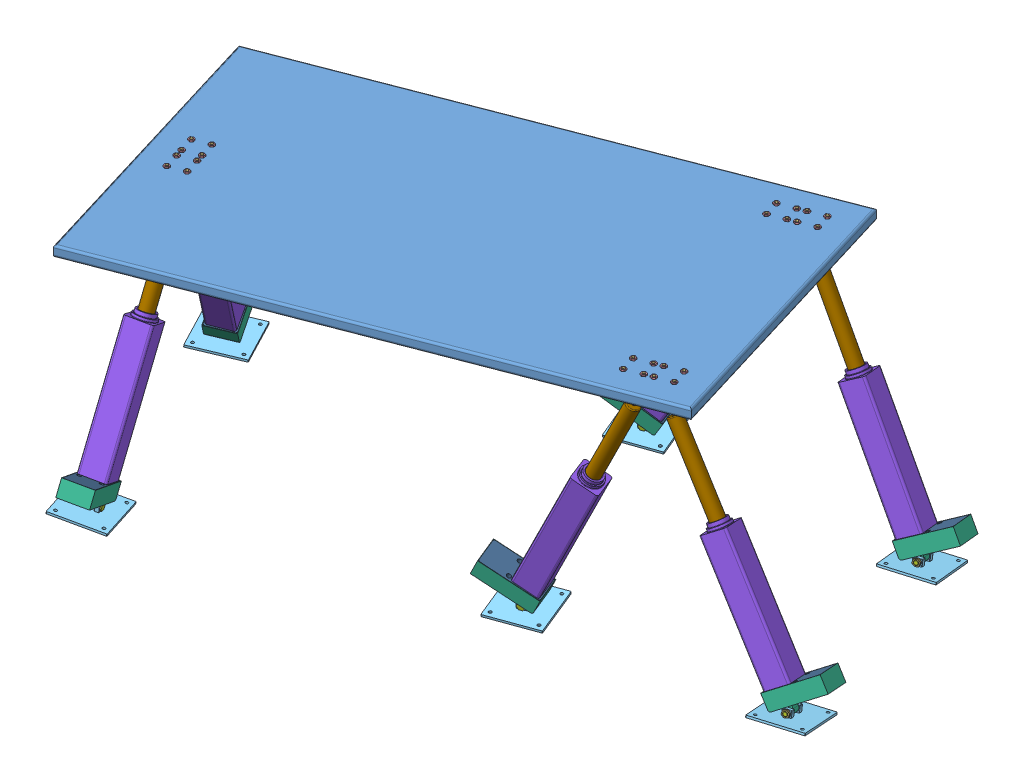
SolidWorks assembly assemblageComplet, configuration Défaut. Lengths in mm.
Overall size (3628.91 1350.38 2383.84).
122 component instances, 12 part files, 6 mates.
Components (placement in the parent):
- assemblagePlaque-1: assemblagePlaque [Défaut] at (1899.0462 -733.3274 2922.0616) x (-0.94396 -0.025016 0.32911) z (-0.327279 -0.058201 -0.943134) size (2500 133.05 1500)
  - plaque-1: plaque [Défaut] at (42.7083 65.3445 2500) size (2500 50 1500)
  - fixationPlaque-1: fixationPlaque [Défaut] at (1110.4083 29.9622 2320) x (-1 0 0) z (0 0 1) size (120 74.05 120)
    - attachePlaque-1: attachePlaque [Défaut] at (-12.3 -35.3823 120) size (120 74.05 120)
  - fixationPlaque-2: fixationPlaque [Défaut] at (1135.0083 29.9622 2680) x (1 0 0) z (0 0 -1) size (120 74.05 120)
    - attachePlaque-1: attachePlaque [Défaut] at (-12.3 -35.3823 120) size (120 74.05 120)
  - fixationPlaque-5: fixationPlaque [Défaut] at (-917.2917 29.9622 3067.7) x (0 0 -1) z (-1 0 0) size (120 74.05 120)
    - attachePlaque-1: attachePlaque [Défaut] at (-12.3 -35.3823 120) size (120 74.05 120)
  - fixationPlaque-6: fixationPlaque [Défaut] at (-797.2917 29.9622 3067.7) x (0 0 -1) z (-1 0 0) size (120 74.05 120)
    - attachePlaque-1: attachePlaque [Défaut] at (-12.3 -35.3823 120) size (120 74.05 120)
  - fixationPlaque-7: fixationPlaque [Défaut] at (-917.2917 29.9622 1907.7) x (0 0 -1) z (-1 0 0) size (120 74.05 120)
    - attachePlaque-1: attachePlaque [Défaut] at (-12.3 -35.3823 120) size (120 74.05 120)
  - fixationPlaque-8: fixationPlaque [Défaut] at (-797.2917 29.9622 1907.7) x (0 0 -1) z (-1 0 0) size (120 74.05 120)
    - attachePlaque-1: attachePlaque [Défaut] at (-12.3 -35.3823 120) size (120 74.05 120)
  - visPlaque-1: visPlaque [Défaut] at (-1077.2917 52.3445 3120) size (24.69 72 26.25)
  - ecrou-1: ecrou [Défaut] at (-1077.2917 115.3445 3120) size (24.81 7 26.32)
  - visPlaque-2: visPlaque [Défaut] at (-1077.2917 52.3445 3040) size (24.69 72 26.25)
  - visPlaque-3: visPlaque [Défaut] at (-997.2917 52.3445 3120) size (24.69 72 26.25)
  - visPlaque-4: visPlaque [Défaut] at (-957.2917 52.3445 3120) size (24.69 72 26.25)
  - visPlaque-5: visPlaque [Défaut] at (-997.2917 52.3445 3040) size (24.69 72 26.25)
  - visPlaque-7: visPlaque [Défaut] at (-957.2917 52.3445 3040) size (24.69 72 26.25)
  - visPlaque-9: visPlaque [Défaut] at (-877.2917 52.3445 3120) size (24.69 72 26.25)
  - visPlaque-10: visPlaque [Défaut] at (-877.2917 52.3445 3040) size (24.69 72 26.25)
  - visPlaque-11: visPlaque [Défaut] at (-877.2917 52.3445 1880) size (24.69 72 26.25)
  - visPlaque-12: visPlaque [Défaut] at (-957.2917 52.3445 1880) size (24.69 72 26.25)
  - visPlaque-13: visPlaque [Défaut] at (-877.2917 52.3445 1960) size (24.69 72 26.25)
  - visPlaque-14: visPlaque [Défaut] at (-957.2917 52.3445 1960) size (24.69 72 26.25)
  - visPlaque-15: visPlaque [Défaut] at (-997.2917 52.3445 1880) size (24.69 72 26.25)
  - visPlaque-16: visPlaque [Défaut] at (-1077.2917 52.3445 1960) size (24.69 72 26.25)
  - visPlaque-17: visPlaque [Défaut] at (-1077.2917 52.3445 1880) size (24.69 72 26.25)
  - visPlaque-18: visPlaque [Défaut] at (-997.2917 52.3445 1960) size (24.69 72 26.25)
  - visPlaque-19: visPlaque [Défaut] at (1162.7083 52.3445 2600) size (24.69 72 26.25)
  - visPlaque-20: visPlaque [Défaut] at (1082.7083 52.3445 2600) size (24.69 72 26.25)
  - visPlaque-21: visPlaque [Défaut] at (1082.7083 52.3445 2520) size (24.69 72 26.25)
  - visPlaque-22: visPlaque [Défaut] at (1162.7083 52.3445 2520) size (24.69 72 26.25)
  - visPlaque-23: visPlaque [Défaut] at (1162.7083 52.3445 2480) size (24.69 72 26.25)
  - visPlaque-25: visPlaque [Défaut] at (1162.7083 52.3445 2400) size (24.69 72 26.25)
  - visPlaque-26: visPlaque [Défaut] at (1082.7083 52.3445 2480) size (24.69 72 26.25)
  - visPlaque-27: visPlaque [Défaut] at (1082.7083 52.3445 2400) size (24.69 72 26.25)
  - ecrou-2: ecrou [Défaut] at (1162.7083 115.3445 2600) size (24.81 7 26.32)
  - ecrou-4: ecrou [Défaut] at (1082.7083 115.3445 2600) size (24.81 7 26.32)
  - ecrou-5: ecrou [Défaut] at (1082.7083 115.3445 2520) size (24.81 7 26.32)
  - ecrou-6: ecrou [Défaut] at (-997.2917 115.3445 3120) size (24.81 7 26.32)
  - ecrou-7: ecrou [Défaut] at (-1077.2917 115.3445 3040) size (24.81 7 26.32)
  - ecrou-8: ecrou [Défaut] at (-997.2917 115.3445 3040) size (24.81 7 26.32)
  - ecrou-9: ecrou [Défaut] at (-957.2917 115.3445 3040) size (24.81 7 26.32)
  - ecrou-11: ecrou [Défaut] at (-877.2917 115.3445 3040) size (24.81 7 26.32)
  - ecrou-12: ecrou [Défaut] at (-957.2917 115.3445 3120) size (24.81 7 26.32)
  - ecrou-13: ecrou [Défaut] at (-877.2917 115.3445 3120) size (24.81 7 26.32)
  - ecrou-14: ecrou [Défaut] at (-1077.2917 115.3445 1880) size (24.81 7 26.32)
  - ecrou-15: ecrou [Défaut] at (-997.2917 115.3445 1880) size (24.81 7 26.32)
  - ecrou-16: ecrou [Défaut] at (-957.2917 115.3445 1880) size (24.81 7 26.32)
  - ecrou-17: ecrou [Défaut] at (-1077.2917 115.3445 1960) size (24.81 7 26.32)
  - ecrou-18: ecrou [Défaut] at (-997.2917 115.3445 1960) size (24.81 7 26.32)
  - ecrou-19: ecrou [Défaut] at (-957.2917 115.3445 1960) size (24.81 7 26.32)
  - ecrou-20: ecrou [Défaut] at (-877.2917 115.3445 1960) size (24.81 7 26.32)
  - ecrou-21: ecrou [Défaut] at (-877.2917 115.3445 1880) size (24.81 7 26.32)
  - ecrou-22: ecrou [Défaut] at (1162.7083 115.3445 2520) size (24.81 7 26.32)
  - ecrou-23: ecrou [Défaut] at (1162.7083 115.3445 2480) size (24.81 7 26.32)
  - ecrou-24: ecrou [Défaut] at (1082.7083 115.3445 2480) size (24.81 7 26.32)
  - ecrou-25: ecrou [Défaut] at (1162.7083 115.3445 2400) size (24.81 7 26.32)
  - ecrou-26: ecrou [Défaut] at (1082.7083 115.3445 2400) size (24.81 7 26.32)
- AssemblementSocleVerin-1: AssemblementSocleVerin [Défaut] at (1913.4027 -2106.2601 67.4221) x (-0.342414 -0.059167 -0.937684) z (0.939482 -0.009636 -0.342463) size (387.8 1201.25 824.63) (flexible)
  - BaseFixationSol-1: BaseFixationSol [Défaut] at (119.3252 189.0503 636.1467) x (0.987313 -0.147005 0.060014) z (-0.059878 0.005348 0.998191) size (240 40 240)
  - BoitierVerin-1: BoitierVerin [Défaut] at (128.1715 273.9331 694.3702) x (-0.018422 -0.48146 -0.876275) z (0.987313 -0.147005 0.060014) size (263 115 133)
  - VisBoititerVerin-1: VisBoititerVerin [Défaut] at (167.4309 207.1631 638.9353) x (0.14706 0.989121 0.003522) z (-0.059878 0.005348 0.998191) size (30.46 97 34.64)
  - assemblageVerin-1: assemblageVerin [Défaut] at (232.7025 260.8151 321.2319) x (0.987484 -0.1387 0.07508) z (0.001434 0.483918 0.875112) size (134.45 1180.45 262.2)
    - BaseVerin-1: BaseVerin [Défaut] at (-78.391 -108.5334 268) size (120 679 120)
    - Verin-1: Verin [Défaut] at (-78.391 292.5867 268) x (-0.924202 0 0.381903) z (-0.381903 0 -0.924202) size (70 662 70)
    - supportMoteur-1: supportMoteur [Défaut] at (-77.2727 -178.5334 332.9904) x (0.017204 0 0.999852) z (-0.999852 0 0.017204) size (260 70 130)
    - attacheVerin-1: attacheVerin [Défaut] at (-78.391 924.5867 268) x (0.999999 0 -0.001089) z (0.001089 0 0.999999) size (40 77.33 40)
  - EcrouAxeSocle-1: EcrouAxeSocle [Défaut] at (83.5092 219.6585 633.8342) x (-0.155337 -0.972556 0.173218) z (0.032903 -0.180343 -0.983053) size (32.03 10 34.64)
- AssemblementSocleVerin-3: AssemblementSocleVerin [Défaut] at (2142.0561 -2104.9187 -0.2086) x (0.342446 0.057092 0.937801) z (-0.939335 0.000085 0.343001) size (381.88 1198.06 838.62) (flexible)
  - BaseFixationSol-1: BaseFixationSol [Défaut] at (-510.5909 194.7617 841.3259) x (0.986382 -0.164066 0.011569) z (-0.0114 0.001968 0.999933) size (240 40 240)
  - BoitierVerin-1: BoitierVerin [Défaut] at (-497.3086 280.161 898.3474) x (-0.071559 -0.491425 -0.867975) z (0.986382 -0.164066 0.011569) size (263 115 133)
  - VisBoititerVerin-1: VisBoititerVerin [Défaut] at (-462.1018 212.0399 841.8447) x (0.164078 0.986447 -0.000071) z (-0.0114 0.001968 0.999933) size (30.46 97 34.64)
  - assemblageVerin-1: assemblageVerin [Défaut] at (-412.2279 260.728 520.5715) x (0.987467 -0.155587 0.026499) z (0.054579 0.494174 0.867648) size (134.45 1180.45 262.2)
    - BaseVerin-1: BaseVerin [Défaut] at (-78.391 -108.5334 268) size (120 679 120)
    - Verin-1: Verin [Défaut] at (-78.391 292.5867 268) x (-0.924202 0 0.381903) z (-0.381903 0 -0.924202) size (70 662 70)
    - supportMoteur-1: supportMoteur [Défaut] at (-77.2727 -178.5334 332.9904) x (0.017204 0 0.999852) z (-0.999852 0 0.017204) size (260 70 130)
    - attacheVerin-1: attacheVerin [Défaut] at (-78.391 924.5867 268) x (0.999999 0 -0.001089) z (0.001089 0 0.999999) size (40 77.33 40)
  - EcrouAxeSocle-1: EcrouAxeSocle [Défaut] at (-545.9442 225.9855 840.8614) x (-0.163505 -0.970523 0.177062) z (-0.017822 -0.176543 -0.984132) size (32.03 10 34.64)
- AssemblementSocleVerin-4: AssemblementSocleVerin [Défaut] at (2303.8055 -2040.4411 1157.8281) x (-0.342402 -0.05932 -0.937679) z (0.939336 -0.000129 -0.342999) size (410.45 1184.18 870.06) (flexible)
  - BaseFixationSol-1: BaseFixationSol [Défaut] at (99.8117 226.2059 683.6223) x (0.984344 -0.162122 0.069157) z (-0.068951 0.006902 0.997596) size (240 40 240)
  - BoitierVerin-1: BoitierVerin [Défaut] at (110.0864 313.6973 738.8652) x (-0.026359 -0.523357 -0.851706) z (0.984344 -0.162122 0.069157) size (263 115 133)
  - VisBoititerVerin-1: VisBoititerVerin [Défaut] at (148.1624 243.579 686.844) x (0.162209 0.986747 0.004385) z (-0.068951 0.006902 0.997596) size (30.46 97 34.64)
  - assemblageVerin-1: assemblageVerin [Défaut] at (214.7817 280.3976 367.0305) x (0.984652 -0.153094 0.083799) z (0.009421 0.526069 0.85039) size (134.45 1180.45 262.2)
    - BaseVerin-1: BaseVerin [Défaut] at (-78.391 -108.5334 268) size (120 679 120)
    - Verin-1: Verin [Défaut] at (-78.391 292.5867 268) x (-0.924202 0 0.381903) z (-0.381903 0 -0.924202) size (70 662 70)
    - supportMoteur-1: supportMoteur [Défaut] at (-77.2727 -178.5334 332.9904) x (0.017204 0 0.999852) z (-0.999852 0 0.017204) size (260 70 130)
    - attacheVerin-1: attacheVerin [Défaut] at (-78.391 924.5867 268) x (0.999999 0 -0.001089) z (0.001089 0 0.999999) size (40 77.33 40)
  - EcrouAxeSocle-1: EcrouAxeSocle [Défaut] at (64.4932 257.3594 680.9656) x (-0.171853 -0.969944 0.172263) z (0.039151 -0.181451 -0.98262) size (32.03 10 34.64)
- AssemblementSocleVerin-5: AssemblementSocleVerin [Défaut] at (2523.5529 -2037.1167 1093.1655) x (0.342447 0.057118 0.937799) z (-0.939301 -0.001561 0.343091) size (344.77 1216.62 750.58) (flexible)
  - BaseFixationSol-1: BaseFixationSol [Défaut] at (-476.6519 139.447 741.7117) x (0.991223 -0.132151 0.003531) z (-0.003463 0.00074 0.999994) size (240 40 240)
  - BoitierVerin-1: BoitierVerin [Défaut] at (-466.4056 219.8573 804.0122) x (-0.051881 -0.413426 -0.909058) z (0.991223 -0.132151 0.003531) size (263 115 133)
  - VisBoititerVerin-1: VisBoititerVerin [Défaut] at (-428.743 158.2809 741.8636) x (0.132153 0.991229 -0.000276) z (-0.003463 0.00074 0.999994) size (30.46 97 34.64)
  - assemblageVerin-1: assemblageVerin [Défaut] at (-379.2667 237.274 426.6072) x (0.991969 -0.125019 0.019169) z (0.03482 0.415639 0.908863) size (134.45 1180.45 262.2)
    - BaseVerin-1: BaseVerin [Défaut] at (-78.391 -108.5334 268) size (120 679 120)
    - Verin-1: Verin [Défaut] at (-78.391 292.5867 268) x (-0.924202 0 0.381903) z (-0.381903 0 -0.924202) size (70 662 70)
    - supportMoteur-1: supportMoteur [Défaut] at (-77.2727 -178.5334 332.9904) x (0.017204 0 0.999852) z (-0.999852 0 0.017204) size (260 70 130)
    - attacheVerin-1: attacheVerin [Défaut] at (-78.391 924.5867 268) x (0.999999 0 -0.001089) z (0.001089 0 0.999999) size (40 77.33 40)
  - EcrouAxeSocle-1: EcrouAxeSocle [Défaut] at (-512.997 169.5138 741.5635) x (-0.130679 -0.975447 0.177275) z (-0.019983 -0.17618 -0.984155) size (32.03 10 34.64)
- AssemblementSocleVerin-6: AssemblementSocleVerin [Défaut] at (163.7194 -2034.6282 1098.1546) x (0.939528 -0.01856 -0.341968) z (0.342033 0.000352 0.939688) size (292.85 1212.77 771.24) (flexible)
  - BaseFixationSol-1: BaseFixationSol [Défaut] at (-200.1351 44.014 357.3957) x (0.996186 -0.086514 0.011348) z (-0.006811 0.05256 0.998595) size (240 40 240)
  - BoitierVerin-1: BoitierVerin [Défaut] at (-193.9454 126.0308 417.2844) x (-0.027413 -0.433778 -0.900603) z (0.996186 -0.086514 0.011348) size (263 115 133)
  - VisBoititerVerin-1: VisBoititerVerin [Défaut] at (-153.132 64.9924 356.6121) x (0.086518 0.99625 0.000189) z (-0.011322 0.000793 0.999936) size (30.46 97 34.64)
  - assemblageVerin-1: assemblageVerin [Défaut] at (-105.4011 139.7384 40.0537) x (0.99651 -0.079039 0.02684) z (0.010271 0.435202 0.900274) size (134.45 1180.45 262.2)
    - BaseVerin-1: BaseVerin [Défaut] at (-78.391 -108.5334 268) size (120 679 120)
    - Verin-1: Verin [Défaut] at (-78.391 292.5867 268) x (-0.924202 0 0.381903) z (-0.381903 0 -0.924202) size (70 662 70)
    - supportMoteur-1: supportMoteur [Défaut] at (-77.2727 -178.5334 332.9904) x (0.017204 0 0.999852) z (-0.999852 0 0.017204) size (260 70 130)
    - attacheVerin-1: attacheVerin [Défaut] at (-78.391 924.5867 268) x (0.999999 0 -0.001089) z (0.001089 0 0.999999) size (40 77.33 40)
  - EcrouAxeSocle-1: EcrouAxeSocle [Défaut] at (-237.8078 72.3461 355.6475) x (-0.087156 -0.980379 0.176807) z (-0.004171 -0.177121 -0.98418) size (32.03 10 34.64)
- AssemblementSocleVerin-7: AssemblementSocleVerin [Défaut] at (227.2636 -2041.1963 1316.271) x (-0.939565 0.016327 0.341982) z (-0.342032 -0.0003 -0.939688) size (319.3 1204.43 808.66) (flexible)
  - BaseFixationSol-1: BaseFixationSol [Défaut] at (193.883 61.1536 1018.1205) x (0.991315 0.041593 -0.124755) z (0.124243 0.014697 0.992143) size (240 40 240)
  - BoitierVerin-1: BoitierVerin [Défaut] at (197.4811 145.5201 1076.8423) x (-0.091161 -0.466391 -0.879869) z (0.991315 0.041593 -0.124755) size (263 115 133)
  - VisBoititerVerin-1: VisBoititerVerin [Défaut] at (237.4147 88.0009 1012.2714) x (-0.043099 0.999027 -0.009402) z (0.124243 0.014697 0.992143) size (30.46 97 34.64)
  - assemblageVerin-1: assemblageVerin [Défaut] at (231.8997 156.5874 690.8062) x (0.992737 0.04961 -0.1096) z (0.074094 0.465607 0.881885) size (134.45 1180.45 262.2)
    - BaseVerin-1: BaseVerin [Défaut] at (-78.391 -108.5334 268) size (120 679 120)
    - Verin-1: Verin [Défaut] at (-78.391 292.5867 268) x (-0.924202 0 0.381903) z (-0.381903 0 -0.924202) size (70 662 70)
    - supportMoteur-1: supportMoteur [Défaut] at (-77.2727 -178.5334 332.9904) x (0.017204 0 0.999852) z (-0.999852 0 0.017204) size (260 70 130)
    - attacheVerin-1: attacheVerin [Défaut] at (-78.391 924.5867 268) x (0.999999 0 -0.001089) z (0.001089 0 0.999999) size (40 77.33 40)
  - EcrouAxeSocle-1: EcrouAxeSocle [Défaut] at (153.1529 84.4655 1022.8756) x (0.06441 -0.980651 0.184867) z (-0.114652 -0.191297 -0.974813) size (32.03 10 34.64)
Mates (geometry in assembly coordinates):
- Coïncidente20: coincident: circle of ?; circle of ?
- Coïncidente23: coincident: circle of ?; circle of ?
- Coïncidente32: coincident: circle of ?; circle of ?
- Coïncidente33: coincident: circle of ?; circle of ?
- Coïncidente34: coincident: circle of ?; circle of ?
- Coïncidente35: coincident: circle of ?; circle of ?
